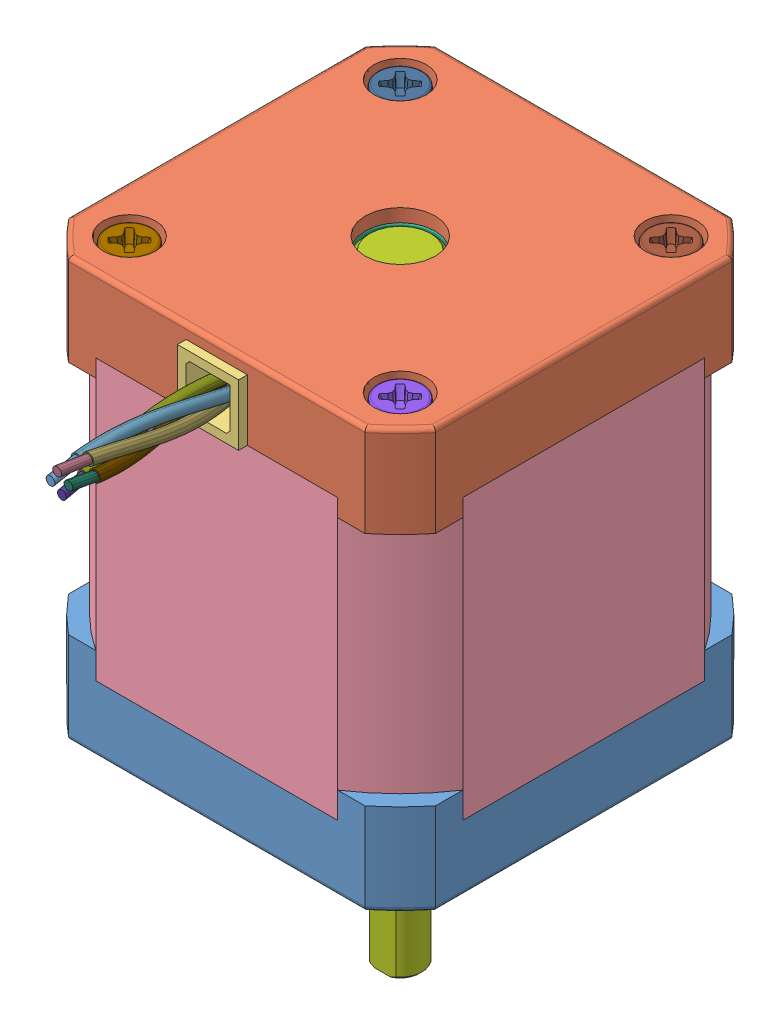
SolidWorks assembly NEMA17 x 48, configuration Default. Lengths in mm.
Overall size (42 72 60).
20 component instances, 19 part files, 0 mates.
Components (placement in the parent):
- NEMA17 x 48.step-1: NEMA17 x 48.step [Default] at origin size (42 72 60)
  - Frontplate.step-1: Frontplate.step [Default] at (0 10.5 0) size (42 12.5 42)
  - Backplate.step-1: Backplate.step [Default] at (0 48 0) size (42 10.5 42)
  - Connenctor.step-1: Connenctor.step [Default] at (0 39.5 22) size (7 7 7)
  - Housing.step-1: Housing.step [Default] at (0 7.5 0) size (42 32 42)
  - Bearing dummy.step-1: Bearing dummy.step [Default] at (0 4 0) size (22 7 22)
  - Bearing dummy 01.step-1: Bearing dummy 01.step [Default] at (0 43 0) size (22 7 22)
  - Core.step-1: Core.step [Default] at origin size (30 70.5 30)
  - M3x40-Screw.step-1: M3x40-Screw.step [Default] at (15.5 45.6 15.5) x (1 0 0) z (0 1 0) size (5.5 5.5 42)
  - M3x40-Screw001.step-1: M3x40-Screw001.step [Default] at (-15.5 45.6 15.5) x (1 0 0) z (0 1 0) size (5.5 5.5 42)
  - M3x40-Screw002.step-1: M3x40-Screw002.step [Default] at (-15.5 45.6 -15.5) x (1 0 0) z (0 1 0) size (5.5 5.5 42)
  - M3x40-Screw003.step-1: M3x40-Screw003.step [Default] at (15.5 45.6 -15.5) x (1 0 0) z (0 1 0) size (5.5 5.5 42)
  - Cable-1of4.step-1: Cable-1of4.step [Default] at (0 43 0) size (3.44 3.69 21)
  - Copper-1of4.step-1: Copper-1of4.step [Default] at (0 43 0) size (2.77 3.05 24)
  - Cable-2of4.step-1: Cable-2of4.step [Default] at (0 43 0) x (0 1 0) z (0 0 1) size (3.44 3.69 21)
  - Copper-4of4.step-1: Copper-4of4.step [Default] at (0 43 0) x (0 -1 0) z (0 0 1) size (2.77 3.05 24)
  - Cable-3of4.step-1: Cable-3of4.step [Default] at (0 43 0) x (-1 0 0) z (0 0 1) size (3.44 3.69 21)
  - Copper-3of4.step-1: Copper-3of4.step [Default] at (0 43 0) x (-1 0 0) z (0 0 1) size (2.77 3.05 24)
  - Cable-4of4.step-1: Cable-4of4.step [Default] at (0 43 0) x (0 -1 0) z (0 0 1) size (3.44 3.69 21)
  - Copper-2of4.step-1: Copper-2of4.step [Default] at (0 43 0) x (0 1 0) z (0 0 1) size (2.77 3.05 24)
